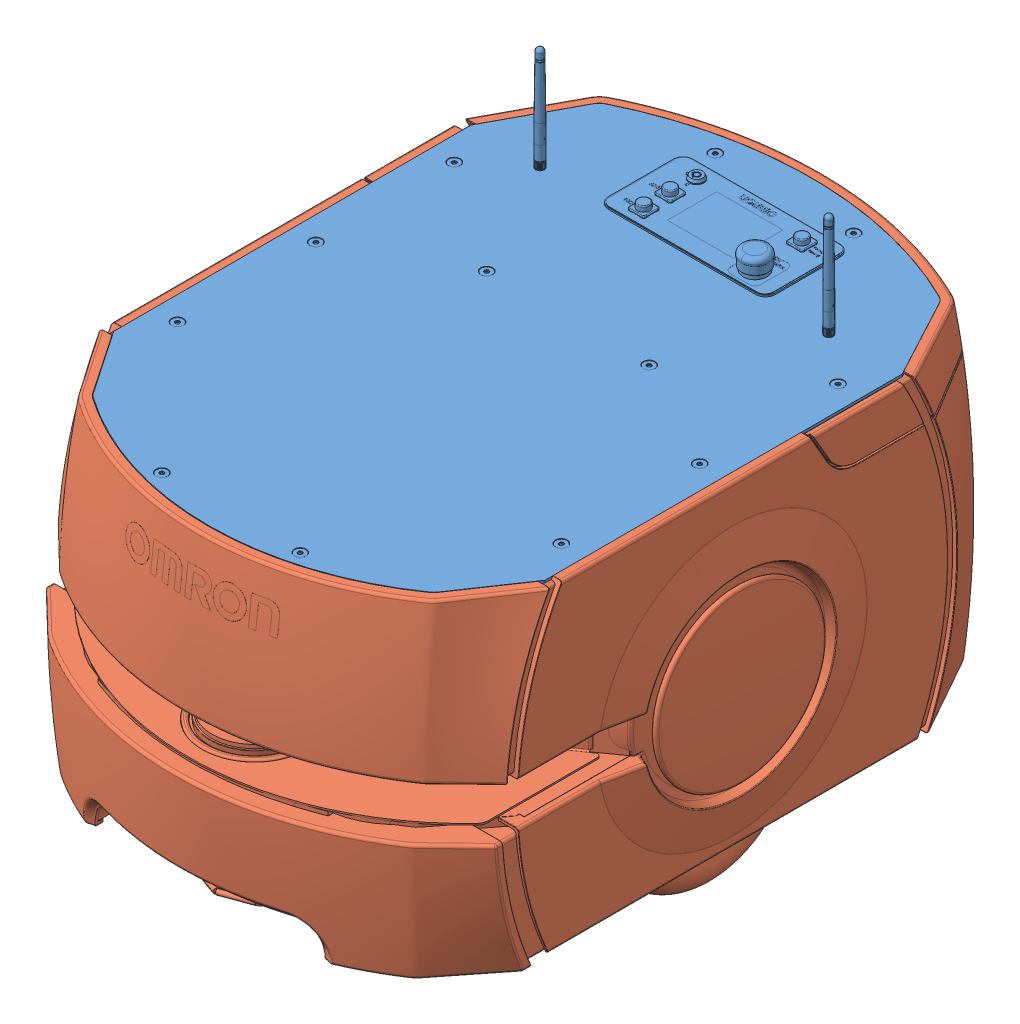
SolidWorks assembly Assem1, configuration Default. Lengths in mm.
Overall size (516.29 492.77 730.45).
2 component instances, 2 part files, 3 mates.
Components (placement in the parent):
- LD Platform Top Plate-1: LD Platform Top Plate [Default] at (174.3607 40.9002 718.8035) size (455.02 142.92 635.74)
- LD Platform-1: LD Platform [Default] at (174.3607 39.8627 718.8035) size (516.29 382.74 730.45)
Mates (geometry in assembly coordinates):
- Coincident1: coincident: plane of LD Platform Top Plate-1 through (-53.1471 422.4209 1038.3653) normal (0 1 0); plane of LD Platform-1 through (208.4868 422.4209 455.9508) normal (0 1 0)
- Concentric1: concentric: circle of LD Platform Top Plate-1; cylinder of LD Platform-1 through (101.3607 414.715 1010.8035) axis (0 -1 0) radius 3.6
- Concentric2: concentric anti-aligned: circle of LD Platform Top Plate-1; circle of LD Platform-1
